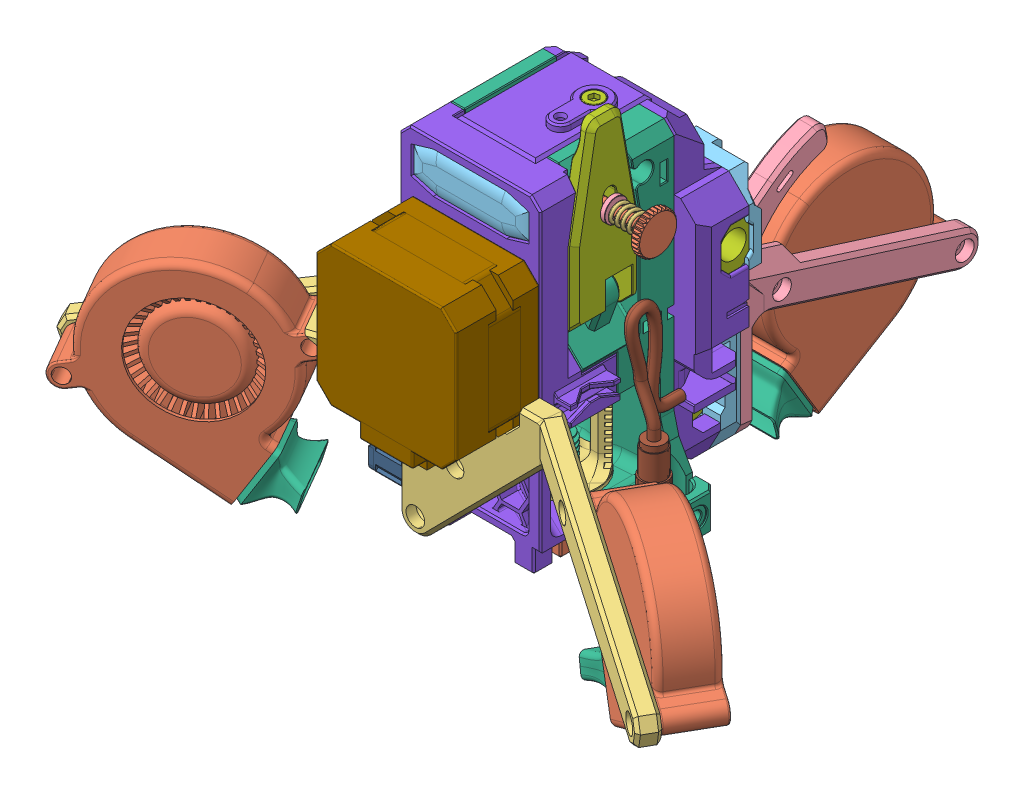
SolidWorks assembly Bondtech Extruder Dragon 3F, configuration Default. Lengths in mm.
Overall size (207.86 123.55 182.65).
64 component instances, 44 part files, 0 mates.
Components (placement in the parent):
- Bondtech Extruder Dragon 3F(2)^Bondtech Extruder Dragon 3F-1: Bondtech Extruder Dragon 3F(2)^Bondtech Extruder Dragon 3F [Default] at origin size (207.86 123.55 182.65) (virtual)
  - Dragon Hotend^Bondtech Extruder Dragon 3F(2)_Bondtech Extruder Dragon 3F-1: Dragon Hotend^Bondtech Extruder Dragon 3F(2)_Bondtech Extruder Dragon 3F [Default] at (35.4836 55.7786 124.4955) x (1 0 0.000004) z (-0.000004 0 1) size (23.77 63.5 26.88) (virtual)
    - Body1-24 (1)^Dragon Hotend_Bondtech Extruder Dragon 3F(2)_Bondtech Extruder Dragon 3F-1: Body1-24 (1)^Dragon Hotend_Bondtech Extruder Dragon 3F(2)_Bondtech Extruder Dragon 3F [Default] at (-10.5 -47.7 -54.8237) x (-0.000004 0 -1) z (1 0 -0.000004) size (8.08 12.5 7) (virtual)
    - Component59^Dragon Hotend_Bondtech Extruder Dragon 3F(2)_Bondtech Extruder Dragon 3F-1: Component59^Dragon Hotend_Bondtech Extruder Dragon 3F(2)_Bondtech Extruder Dragon 3F [Default] at origin size (16 11.5 23) (virtual)
    - Component60^Dragon Hotend_Bondtech Extruder Dragon 3F(2)_Bondtech Extruder Dragon 3F-1: Component60^Dragon Hotend_Bondtech Extruder Dragon 3F(2)_Bondtech Extruder Dragon 3F [Default] at origin size (23.77 31 23.77) (virtual)
    - Component61^Dragon Hotend_Bondtech Extruder Dragon 3F(2)_Bondtech Extruder Dragon 3F-1: Component61^Dragon Hotend_Bondtech Extruder Dragon 3F(2)_Bondtech Extruder Dragon 3F [Default] at origin size (20.4 18 21) (virtual)
    - Component62^Dragon Hotend_Bondtech Extruder Dragon 3F(2)_Bondtech Extruder Dragon 3F-1: Component62^Dragon Hotend_Bondtech Extruder Dragon 3F(2)_Bondtech Extruder Dragon 3F [Default] at origin size (2 31.5 2) (virtual)
    - Component63^Dragon Hotend_Bondtech Extruder Dragon 3F(2)_Bondtech Extruder Dragon 3F-1: Component63^Dragon Hotend_Bondtech Extruder Dragon 3F(2)_Bondtech Extruder Dragon 3F [Default] at origin size (8.93 18.8 8) (virtual)
  - bondtech_x_carriage_mk3s^Bondtech Extruder Dragon 3F(2)_Bondtech Extruder Dragon 3F-1: bondtech_x_carriage_mk3s^Bondtech Extruder Dragon 3F(2)_Bondtech Extruder Dragon 3F [Default] x (0 -1 0) z (0 0 -1) size (93.5 52 22.4) (virtual)
    - lm8uu^bondtech_x_carriage_mk3s_Bondtech Extruder Dragon 3F(2)_Bondtech Extruder Dragon 3F-1: lm8uu^bondtech_x_carriage_mk3s_Bondtech Extruder Dragon 3F(2)_Bondtech Extruder Dragon 3F [Default] at (-82.8786 -48.5838 -41.6717) size (15 24 15) (virtual)
    - x_carriage^bondtech_x_carriage_mk3s_Bondtech Extruder Dragon 3F(2)_Bondtech Extruder Dragon 3F-1: x_carriage^bondtech_x_carriage_mk3s_Bondtech Extruder Dragon 3F(2)_Bondtech Extruder Dragon 3F [Default] at (-111.8786 -49.9838 -52.6717) size (93.5 52 22.4) (virtual)
    - lm8uu^bondtech_x_carriage_mk3s_Bondtech Extruder Dragon 3F(2)_Bondtech Extruder Dragon 3F-2: lm8uu^bondtech_x_carriage_mk3s_Bondtech Extruder Dragon 3F(2)_Bondtech Extruder Dragon 3F [Default] at (-82.8786 -23.3838 -41.6717) size (15 24 15) (virtual)
    - lm8uu^bondtech_x_carriage_mk3s_Bondtech Extruder Dragon 3F(2)_Bondtech Extruder Dragon 3F-3: lm8uu^bondtech_x_carriage_mk3s_Bondtech Extruder Dragon 3F(2)_Bondtech Extruder Dragon 3F [Default] at (-37.8786 -35.9838 -41.6717) size (15 24 15) (virtual)
  - T_Nema17_25mm^Bondtech Extruder Dragon 3F(2)_Bondtech Extruder Dragon 3F-1: T_Nema17_25mm^Bondtech Extruder Dragon 3F(2)_Bondtech Extruder Dragon 3F [Default] at (20.7338 77.8786 117.6717) x (1 0 0) z (0 0 -1) size (42 48.5 47) (virtual)
  - Noctua-NF-A4x101^Bondtech Extruder Dragon 3F(2)_Bondtech Extruder Dragon 3F-1: Noctua-NF-A4x101^Bondtech Extruder Dragon 3F(2)_Bondtech Extruder Dragon 3F [Default] at (-3.5153 40.5507 72.6717) x (0 0 1) z (-1 0 0) size (40.14 40.18 12) (virtual)
  - PINDA Probe1^Bondtech Extruder Dragon 3F(2)_Bondtech Extruder Dragon 3F-1: PINDA Probe1^Bondtech Extruder Dragon 3F(2)_Bondtech Extruder Dragon 3F [Default] at (47.9838 32.7995 64.6717) x (1 0 0) z (0 -1 0) size (9.4 16.55 69) (virtual)
  - HexPlug^Bondtech Extruder Dragon 3F(2)_Bondtech Extruder Dragon 3F-1: HexPlug^Bondtech Extruder Dragon 3F(2)_Bondtech Extruder Dragon 3F [Default] at origin size (6.35 6.43 3.31) (virtual)
  - Motorgear_17T_without_setscrew^Bondtech Extruder Dragon 3F(2)_Bondtech Extruder Dragon 3F-1: Motorgear_17T_without_setscrew^Bondtech Extruder Dragon 3F(2)_Bondtech Extruder Dragon 3F [Default] at (20.7338 77.8786 85.6717) x (-0.106111 -0.994354 0) z (0 0 1) size (10.01 10.03 13) (virtual)
  - stift 3x20^Bondtech Extruder Dragon 3F(2)_Bondtech Extruder Dragon 3F-1: stift 3x20^Bondtech Extruder Dragon 3F(2)_Bondtech Extruder Dragon 3F [Default] at (29.2338 94.6286 83.6717) x (1 0 0) z (0 1 0) size (3 20 3) (virtual)
  - stift 3x32^Bondtech Extruder Dragon 3F(2)_Bondtech Extruder Dragon 3F-1: stift 3x32^Bondtech Extruder Dragon 3F(2)_Bondtech Extruder Dragon 3F [Default] at (36.2338 79.1286 60.1717) x (0.913119 -0.407692 0) z (-0.407692 -0.913119 0) size (3 32 3) (virtual)
  - Axel 5mm^Bondtech Extruder Dragon 3F(2)_Bondtech Extruder Dragon 3F-1: Axel 5mm^Bondtech Extruder Dragon 3F(2)_Bondtech Extruder Dragon 3F [Default] at (20.7338 94.6286 64.1707) x (0 0 1) z (-0.996987 0.077566 0) size (28 5.1 5.18) (virtual)
  - Gear1^Bondtech Extruder Dragon 3F(2)_Bondtech Extruder Dragon 3F-1: Gear1^Bondtech Extruder Dragon 3F(2)_Bondtech Extruder Dragon 3F [Default] at (20.7338 94.6286 85.4717) x (0.077566 0.996987 0) z (0 0 1) size (25.97 26 7) (virtual)
  - Direct_Drivegear_without_setscrew^Bondtech Extruder Dragon 3F(2)_Bondtech Extruder Dragon 3F-1: Direct_Drivegear_without_setscrew^Bondtech Extruder Dragon 3F(2)_Bondtech Extruder Dragon 3F [Default] at (29.2338 94.6286 76.6717) x (0.469401 -0.882985 0) z (0 0 1) size (9.47 9.43 14) (virtual)
  - Direct_Drivegear^Bondtech Extruder Dragon 3F(2)_Bondtech Extruder Dragon 3F-1: Direct_Drivegear^Bondtech Extruder Dragon 3F(2)_Bondtech Extruder Dragon 3F [Default] at (20.7338 94.6286 76.6707) x (-0.077566 -0.996987 0) z (0 0 1) size (9.47 9.43 14) (virtual)
  - Thumbscrew_din653_m3_20^Bondtech Extruder Dragon 3F(2)_Bondtech Extruder Dragon 3F-1: Thumbscrew_din653_m3_20^Bondtech Extruder Dragon 3F(2)_Bondtech Extruder Dragon 3F [Default] at (55.2338 105.8786 73.1717) x (0 -0.906944 0.421251) z (0 0.421251 0.906944) size (12.09 22.5 12.08) (virtual)
  - F6fors 2915^Bondtech Extruder Dragon 3F(2)_Bondtech Extruder Dragon 3F-1: F6fors 2915^Bondtech Extruder Dragon 3F(2)_Bondtech Extruder Dragon 3F [Default] at (55.2338 105.8786 73.1717) x (0 1 0) z (0 0 1) size (6.23 10.01 6.23) (virtual)
  - Lock_washer_Nylon_EssentraSR 1940^Bondtech Extruder Dragon 3F(2)_Bondtech Extruder Dragon 3F-1: Lock_washer_Nylon_EssentraSR 1940^Bondtech Extruder Dragon 3F(2)_Bondtech Extruder Dragon 3F [Default] at (43.8338 105.8786 73.1717) x (0 -0.999948 -0.010151) z (0 -0.010151 0.999948) size (7 1.4 7) (virtual)
  - Dekal^Bondtech Extruder Dragon 3F(2)_Bondtech Extruder Dragon 3F-1: Dekal^Bondtech Extruder Dragon 3F(2)_Bondtech Extruder Dragon 3F [Default] at (20.8588 107.7286 91.6717) size (35 12 1.3) (virtual)
  - NewMK3_Rear_Orginal.V2^Bondtech Extruder Dragon 3F(2)_Bondtech Extruder Dragon 3F-1: NewMK3_Rear_Orginal.V2^Bondtech Extruder Dragon 3F(2)_Bondtech Extruder Dragon 3F [Default] at origin size (64.25 98.5 29.22) (virtual)
  - Hinge_Mirrored^Bondtech Extruder Dragon 3F(2)_Bondtech Extruder Dragon 3F-1: Hinge_Mirrored^Bondtech Extruder Dragon 3F(2)_Bondtech Extruder Dragon 3F [Default] at (20.7338 94.6286 63.6717) size (18 55 20) (virtual)
  - Extruder_Front.v2^Bondtech Extruder Dragon 3F(2)_Bondtech Extruder Dragon 3F-1: Extruder_Front.v2^Bondtech Extruder Dragon 3F(2)_Bondtech Extruder Dragon 3F [Default] at (-21.2425 89.1286 92.1717) size (56.25 98 24.78) (virtual)
  - Lager 5x8x2^Bondtech Extruder Dragon 3F(2)_Bondtech Extruder Dragon 3F-1: Lager 5x8x2^Bondtech Extruder Dragon 3F(2)_Bondtech Extruder Dragon 3F [Default] at (20.7338 94.6286 63.6707) x (0.132022 -0.991247 0) z (0 0 1) size (8 8 2.5) (virtual)
  - Lager 5x8x2^Bondtech Extruder Dragon 3F(2)_Bondtech Extruder Dragon 3F-2: Lager 5x8x2^Bondtech Extruder Dragon 3F(2)_Bondtech Extruder Dragon 3F [Default] at (20.7338 94.6286 88.9717) x (0.2227 -0.974887 0) z (0 0 1) size (8 8 2.5) (virtual)
  - K3x5x7^Bondtech Extruder Dragon 3F(2)_Bondtech Extruder Dragon 3F-1: K3x5x7^Bondtech Extruder Dragon 3F(2)_Bondtech Extruder Dragon 3F [Default] at (29.2338 94.6286 77.1717) x (0.993908 -0.110211 0) z (0 0 1) size (4.8 4.85 7) (virtual)
  - K3x5x7^Bondtech Extruder Dragon 3F(2)_Bondtech Extruder Dragon 3F-2: K3x5x7^Bondtech Extruder Dragon 3F(2)_Bondtech Extruder Dragon 3F [Default] at (29.2338 94.6286 70.1717) x (0.989112 -0.147165 0) z (0 0 1) size (4.8 4.85 7) (virtual)
  - Trisert 136-M3^Bondtech Extruder Dragon 3F(2)_Bondtech Extruder Dragon 3F-1: Trisert 136-M3^Bondtech Extruder Dragon 3F(2)_Bondtech Extruder Dragon 3F [Default] at (22.2338 40.6036 92.4717) x (0.643026 0.765845 0) z (0.765845 -0.643026 0) size (4.3 5.2 4.28) (virtual)
  - Trisert 136-M3^Bondtech Extruder Dragon 3F(2)_Bondtech Extruder Dragon 3F-2: Trisert 136-M3^Bondtech Extruder Dragon 3F(2)_Bondtech Extruder Dragon 3F [Default] at (37.7338 105.8786 73.1717) x (0 0.99016 0.139938) z (0 0.139938 -0.99016) size (4.3 5.2 4.28) (virtual)
  - Trisert 136-M3^Bondtech Extruder Dragon 3F(2)_Bondtech Extruder Dragon 3F-3: Trisert 136-M3^Bondtech Extruder Dragon 3F(2)_Bondtech Extruder Dragon 3F [Default] at (4.9838 105.3786 80.1717) x (-0.531806 0.846866 0) z (-0.846866 -0.531806 0) size (4.3 5.2 4.28) (virtual)
  - hex thin nut gradeb_iso_ISO - 4036 - M3 - N^Bondtech Extruder Dragon 3F(2)_Bondtech Extruder Dragon 3F-1: hex thin nut gradeb_iso_ISO - 4036 - M3 - N^Bondtech Extruder Dragon 3F(2)_Bondtech Extruder Dragon 3F [Default] at (13.2338 62.3786 83.4717) x (0 -1 0) z (0 0 1) size (5.5 6.35 1.8) (virtual)
  - MC6S M3_M3x45^Bondtech Extruder Dragon 3F(2)_Bondtech Extruder Dragon 3F-1: MC6S M3_M3x45^Bondtech Extruder Dragon 3F(2)_Bondtech Extruder Dragon 3F [Default] at (13.2338 62.3786 37.6717) x (0 0 1) z (-0.989964 0.141319 0) size (48 5.5 5.5) (virtual)
  - MC6S M3_M3x40^Bondtech Extruder Dragon 3F(2)_Bondtech Extruder Dragon 3F-1: MC6S M3_M3x40^Bondtech Extruder Dragon 3F(2)_Bondtech Extruder Dragon 3F [Default] at (4.9838 105.3786 44.6717) x (0 0 1) z (-0.989964 0.141319 0) size (43 5.5 5.5) (virtual)
  - MC6S M3_M3x40^Bondtech Extruder Dragon 3F(2)_Bondtech Extruder Dragon 3F-2: MC6S M3_M3x40^Bondtech Extruder Dragon 3F(2)_Bondtech Extruder Dragon 3F [Default] at (36.2338 62.3786 37.6717) x (0 0 1) z (-0.591351 -0.806415 0) size (43 5.5 5.5) (virtual)
  - MC6S M3_M3x25^Bondtech Extruder Dragon 3F(2)_Bondtech Extruder Dragon 3F-1: MC6S M3_M3x25^Bondtech Extruder Dragon 3F(2)_Bondtech Extruder Dragon 3F [Default] at (5.2338 62.3786 66.6717) x (0 0 1) z (-0.231828 0.972757 0) size (28 5.5 5.5) (virtual)
  - MC6S M3_M3x12^Bondtech Extruder Dragon 3F(2)_Bondtech Extruder Dragon 3F-1: MC6S M3_M3x12^Bondtech Extruder Dragon 3F(2)_Bondtech Extruder Dragon 3F [Default] at (5.2338 93.3786 80.1717) x (0 0 1) z (0.866076 0.499912 0) size (15 5.5 5.5) (virtual)
  - MC6S M3_M3x12^Bondtech Extruder Dragon 3F(2)_Bondtech Extruder Dragon 3F-2: MC6S M3_M3x12^Bondtech Extruder Dragon 3F(2)_Bondtech Extruder Dragon 3F [Default] at (-9.0934 24.3786 56.6717) x (1 0 0) z (0 0.516976 0.856) size (15 5.5 5.5) (virtual)
  - MC6S M3_M3x12^Bondtech Extruder Dragon 3F(2)_Bondtech Extruder Dragon 3F-3: MC6S M3_M3x12^Bondtech Extruder Dragon 3F(2)_Bondtech Extruder Dragon 3F [Default] at (-9.0934 56.3786 56.6717) x (1 0 0) z (0 0.374716 0.92714) size (15 5.5 5.5) (virtual)
  - MC6S M3_M3x12^Bondtech Extruder Dragon 3F(2)_Bondtech Extruder Dragon 3F-4: MC6S M3_M3x12^Bondtech Extruder Dragon 3F(2)_Bondtech Extruder Dragon 3F [Default] at (-9.0934 56.3786 88.6717) x (1 0 0) z (0 0.271083 0.962556) size (15 5.5 5.5) (virtual)
  - MC6S M3_M3x12^Bondtech Extruder Dragon 3F(2)_Bondtech Extruder Dragon 3F-5: MC6S M3_M3x12^Bondtech Extruder Dragon 3F(2)_Bondtech Extruder Dragon 3F [Default] at (-9.0934 24.3786 88.6717) x (1 0 0) z (0 -0.697239 0.716839) size (15 5.5 5.5) (virtual)
  - MC6S M3_ISO 4762 M3 x 8 - 8N^Bondtech Extruder Dragon 3F(2)_Bondtech Extruder Dragon 3F-1: MC6S M3_ISO 4762 M3 x 8 - 8N^Bondtech Extruder Dragon 3F(2)_Bondtech Extruder Dragon 3F [Default] at (36.2338 62.3786 83.6717) x (0 0 1) z (-0.818153 -0.575001 0) size (11 5.5 5.5) (virtual)
  - M3x2_M3x3^Bondtech Extruder Dragon 3F(2)_Bondtech Extruder Dragon 3F-1: M3x2_M3x3^Bondtech Extruder Dragon 3F(2)_Bondtech Extruder Dragon 3F [Default] at (21.3174 83.3476 79.6717) x (-0.106111 -0.994354 0) z (0.005838 -0.000623 -0.999983) size (3 3 3) (virtual)
  - M3x2_M3x3^Bondtech Extruder Dragon 3F(2)_Bondtech Extruder Dragon 3F-2: M3x2_M3x3^Bondtech Extruder Dragon 3F(2)_Bondtech Extruder Dragon 3F [Default] at (21.1216 99.6136 73.6707) x (-0.077566 -0.996987 0) z (-0.052637 0.004095 -0.998605) size (3 3 3) (virtual)
  - Nut M3 Square^Bondtech Extruder Dragon 3F(2)_Bondtech Extruder Dragon 3F-1: Nut M3 Square^Bondtech Extruder Dragon 3F(2)_Bondtech Extruder Dragon 3F [Default] at (37.0338 62.2786 74.5403) x (0 1 0) z (1 0 0) size (5.4 1.71 5.4) (virtual)
  - Nut M3 Square^Bondtech Extruder Dragon 3F(2)_Bondtech Extruder Dragon 3F-2: Nut M3 Square^Bondtech Extruder Dragon 3F(2)_Bondtech Extruder Dragon 3F [Default] at (41.546 23.5286 65.4718) x (0 1 0) z (0 0 1) size (5.4 1.71 5.4) (virtual)
  - T_FAN_5015_BLOWER1^Bondtech Extruder Dragon 3F(2)_Bondtech Extruder Dragon 3F-1: T_FAN_5015_BLOWER1^Bondtech Extruder Dragon 3F(2)_Bondtech Extruder Dragon 3F [Default] at (96.7129 46.1353 102.1937) x (-0.742327 -0.515038 -0.428586) z (-0.446035 0.857167 -0.257521) size (51.75 17.19 52.1) (virtual)
  - T_FAN_5015_BLOWER1^Bondtech Extruder Dragon 3F(2)_Bondtech Extruder Dragon 3F-2: T_FAN_5015_BLOWER1^Bondtech Extruder Dragon 3F(2)_Bondtech Extruder Dragon 3F [Default] at (-39.0456 46.1353 115.53) x (0.74233 -0.515038 -0.428581) z (0.446037 0.857167 -0.257517) size (51.75 17.19 52.1) (virtual)
  - T_FAN_5015_BLOWER1^Bondtech Extruder Dragon 3F(2)_Bondtech Extruder Dragon 3F-3: T_FAN_5015_BLOWER1^Bondtech Extruder Dragon 3F(2)_Bondtech Extruder Dragon 3F [Default] at (17.2841 46.1353 -8.7085) x (-0.000003 -0.515038 0.857167) z (-0.000002 0.857167 0.515038) size (51.75 17.19 52.1) (virtual)
  - Front Fan Holder^Bondtech Extruder Dragon 3F(2)_Bondtech Extruder Dragon 3F-1: Front Fan Holder^Bondtech Extruder Dragon 3F(2)_Bondtech Extruder Dragon 3F [Default] at origin size (197.36 48.46 56.25) (virtual)
  - Rear Fan Holder^Bondtech Extruder Dragon 3F(2)_Bondtech Extruder Dragon 3F-1: Rear Fan Holder^Bondtech Extruder Dragon 3F(2)_Bondtech Extruder Dragon 3F [Default] at origin size (19.86 62.87 73.17) (virtual)
  - x_carriage_back_mk3s^Bondtech Extruder Dragon 3F(2)_Bondtech Extruder Dragon 3F-1: x_carriage_back_mk3s^Bondtech Extruder Dragon 3F(2)_Bondtech Extruder Dragon 3F [Default] at (41.4838 22.8786 30.4717) x (0 1 0) z (0 0 1) size (75.21 52 7.8) (virtual)
  - Fan Duct^Bondtech Extruder Dragon 3F(2)_Bondtech Extruder Dragon 3F-1: Fan Duct^Bondtech Extruder Dragon 3F(2)_Bondtech Extruder Dragon 3F [Default] at origin size (24.22 18.24 23.72) (virtual)
  - MC6S_ISO 4762 M3 x 10 - 10N^Bondtech Extruder Dragon 3F(2)_Bondtech Extruder Dragon 3F-1: MC6S_ISO 4762 M3 x 10 - 10N^Bondtech Extruder Dragon 3F(2)_Bondtech Extruder Dragon 3F [Default] at (24.9838 118.3786 59.6717) x (0 -1 0) z (0.230463 0 0.973081) size (13 5.5 5.5) (virtual)
  - Sensor Cover MK3s^Bondtech Extruder Dragon 3F(2)_Bondtech Extruder Dragon 3F-1: Sensor Cover MK3s^Bondtech Extruder Dragon 3F(2)_Bondtech Extruder Dragon 3F [Default] at (30.9838 113.3786 48.4717) x (-1 0 0) z (0 0 -1) size (24 5 34.7) (virtual)
  - Fan Duct^Bondtech Extruder Dragon 3F(2)_Bondtech Extruder Dragon 3F-2: Fan Duct^Bondtech Extruder Dragon 3F(2)_Bondtech Extruder Dragon 3F [Default] at (-22.8618 0 126.1442) x (-0.5 0 -0.866025) z (0.866025 0 -0.5) size (24.22 18.24 23.72) (virtual)
  - Fan Duct^Bondtech Extruder Dragon 3F(2)_Bondtech Extruder Dragon 3F-3: Fan Duct^Bondtech Extruder Dragon 3F(2)_Bondtech Extruder Dragon 3F [Default] at (97.8132 0 82.871) x (-0.5 0 0.866025) z (-0.866025 0 -0.5) size (24.22 18.24 23.72) (virtual)
